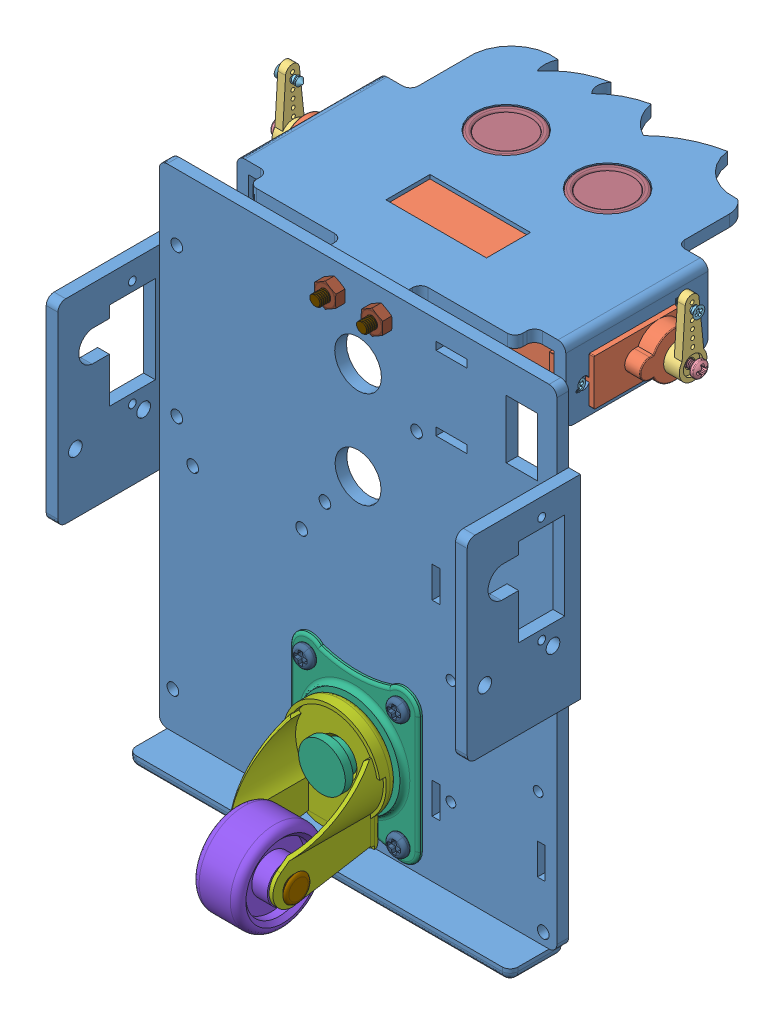
SolidWorks assembly DYOR_3D_OL_AR, configuration Predeterminado. Lengths in mm.
Overall size (109.66 136.43 112.93).
67 component instances, 23 part files, 18 mates.
Components (placement in the parent):
- Base-1: Base [Predeterminado] at (60.418 -80.9125 12.5389) size (108 128.45 29)
- AR1-1: AR1 [Predeterminado] at (-138.059 230.6023 -125.9386) size (34.06 21.84 31.9)
  - sg90-2: sg90 [Default] at (126.818 -193.0635 98.9775) x (0 0 1) z (0 -1 0) size (31.9 29.9 11.8)
  - SG90 plastic Horn-2: SG90 plastic Horn [Default] at (97.368 -198.9635 104.8775) x (0 0.999767 0.021606) z (0 -0.021606 0.999767) size (19.4 4 7.07)
  - (M2_3_mm)_90116A007_METRIC 316 SS PAN HEAD PHILLIPS MACHINE SCREW-2: (M2_3_mm)_90116A007_METRIC 316 SS PAN HEAD PHILLIPS MACHINE SCREW [90116A007] at (97.368 -198.9635 104.8775) x (0 0 1) z (-1 0 0) size (4 4 4.68)
  - M2x6 SelfTap Screw-1: M2x6 SelfTap Screw [Predeterminado] at (93.868 -186.4635 104.8775) x (0 0.924225 0.381849) z (-1 0 0) size (3.4 3.28 6)
  - M2x6 SelfTap Screw-3: M2x6 SelfTap Screw [Predeterminado] at (105.418 -198.9635 123.8775) x (0 0.924225 0.381849) z (-1 0 0) size (3.4 3.28 6)
  - M2x6 SelfTap Screw-5: M2x6 SelfTap Screw [Predeterminado] at (105.418 -198.9635 96.5775) x (0 0.924225 0.381849) z (-1 0 0) size (3.4 3.28 6)
- AR2-1: AR2 [Predeterminado] at (-145.0774 230.6023 -125.9386) size (34.06 21.82 31.9)
  - sg90-1: sg90 [Default] at (175.3764 -204.8635 98.9775) x (0 0 1) z (0 1 0) size (31.9 29.9 11.8)
  - SG90 plastic Horn-1: SG90 plastic Horn [Default] at (204.8264 -198.9635 104.8775) x (0 0.999858 0.016879) z (0 0.016879 -0.999858) size (19.4 4 7.07)
  - (M2_3_mm)_90116A007_METRIC 316 SS PAN HEAD PHILLIPS MACHINE SCREW-1: (M2_3_mm)_90116A007_METRIC 316 SS PAN HEAD PHILLIPS MACHINE SCREW [90116A007] at (204.8264 -198.9635 104.8775) x (0 0 -1) z (1 0 0) size (4 4 4.68)
  - M2x6 SelfTap Screw-2: M2x6 SelfTap Screw [Predeterminado] at (208.3264 -186.4635 104.8775) x (0 -0.924225 -0.381849) z (1 0 0) size (3.4 3.28 6)
  - M2x6 SelfTap Screw-4: M2x6 SelfTap Screw [Predeterminado] at (196.7764 -198.9635 123.8775) x (0 -0.924225 -0.381849) z (1 0 0) size (3.4 3.28 6)
  - M2x6 SelfTap Screw-6: M2x6 SelfTap Screw [Predeterminado] at (196.7764 -198.9635 96.5775) x (0 -0.924225 -0.381849) z (1 0 0) size (3.4 3.28 6)
- CA-1: CA [Predeterminado] at (-2.207 18.0036 0) size (33 45.94 43.2)
  - Caster Wheel-1: Caster Wheel [Default] at (57.6387 -78.841 57.7572) x (0 1 0) z (-1 0 0) size (45.94 37.59 33)
    - caster holder-1: caster holder [Default] at (-24.0751 44.7184 29.5137) x (1 0 0) z (0 0 -1) size (39 9.27 33)
    - holder-1: holder [Default] at (-1.5751 42.9484 46.0137) x (0 0 1) z (1 0 0) size (25 28.07 31.31)
    - caster wheel-1: caster wheel [Default] at (-15.6961 19.9484 46.0137) x (0.997275 0.073773 0) z (0 0 1) size (23 23 14)
    - Part4-1: Part4 [Default] at (-15.6961 19.9484 55.0137) x (-0.978448 0.206495 0) z (0 0 -1) size (7 7 20)
  - M3x6 Philips Screw-1: M3x6 Philips Screw [Predeterminado] at (23.625 -65.4161 13.5389) size (5.3 5.3 7.81)
  - M3x6 Philips Screw-2: M3x6 Philips Screw [Predeterminado] at (-0.375 -65.4161 13.5389) size (5.3 5.3 7.81)
  - M3x6 Philips Screw-3: M3x6 Philips Screw [Predeterminado] at (-0.375 -95.4161 13.5389) size (5.3 5.3 7.81)
  - M3x6 Philips Screw-4: M3x6 Philips Screw [Predeterminado] at (23.625 -95.4161 13.5389) size (5.3 5.3 7.81)
  - M3 Nut-1: M3 Nut [Predeterminado] at (23.625 -65.4161 11.0389) size (6.27 6.27 2.71)
  - M3 Nut-2: M3 Nut [Predeterminado] at (-0.375 -65.4161 11.0389) size (6.27 6.27 2.71)
  - M3 Nut-3: M3 Nut [Predeterminado] at (-0.375 -95.4161 11.0389) size (6.27 6.27 2.71)
  - M3 Nut-4: M3 Nut [Predeterminado] at (23.625 -95.4161 11.0389) size (6.27 6.27 2.71)
- HC-SR04 Ping Sensor-1: HC-SR04 Ping Sensor [Default] at (9.418 28.7888 -38.4617) x (0 0 -1) z (0 1 0) size (25.18 45 18.07)
  - PCB-1: PCB [Default] at origin size (20.5 45 1.75)
  - Transducer-1: Transducer [Default] at (0 -13 13.25) x (1 0 0) z (0 -1 0) size (15.88 12 15.88)
  - Transducer-2: Transducer [Default] at (0 13 13.25) x (1 0 0) z (0 -1 0) size (15.88 12 15.88)
  - 3 Pin Header 90 Degree-1: 3 Pin Header 90 Degree [Default] at (8.4275 0 -1.25) x (-1 0 0) z (0 -1 0) size (8 7.82 10)
  - 14 Pin SMT-1: 14 Pin SMT [Default] at (-0.35 -18.5 -0.85) x (0 -1 0) z (1 0 0) size (6 1.6 8.8)
  - 14 Pin SMT-2: 14 Pin SMT [Default] at (0 -0.3826 -0.85) x (1 0 0) z (0 1 0) size (6 1.6 8.8)
  - 14 Pin SMT-3: 14 Pin SMT [Default] at (0 17.5274 -0.85) x (1 0 0) z (0 1 0) size (6 1.6 8.8)
  - Cap1 SMT-1: Cap1 SMT [Default] at (-1.755 7.4774 -0.9689) x (0 1 0) z (-1 0 0) size (4.5 1.84 1.75)
  - Cap1 SMT-2: Cap1 SMT [Default] at (6.835 7.4774 -0.9689) x (0 1 0) z (-1 0 0) size (4.5 1.84 1.75)
  - Cap1 SMT-3: Cap1 SMT [Default] at (-6.835 7.4774 -0.9689) x (0 1 0) z (-1 0 0) size (4.5 1.84 1.75)
  - Cap1 SMT-4: Cap1 SMT [Default] at (4.295 7.4774 -0.9689) x (0 1 0) z (-1 0 0) size (4.5 1.84 1.75)
  - Cap1 SMT-5: Cap1 SMT [Default] at (1.755 7.4774 -0.9689) x (0 1 0) z (-1 0 0) size (4.5 1.84 1.75)
  - Cap1 SMT-6: Cap1 SMT [Default] at (-4.295 7.4774 -0.9689) x (0 1 0) z (-1 0 0) size (4.5 1.84 1.75)
  - HC-SR04 Crystal-1: HC-SR04 Crystal [Default] at (-8.3 0 1.75) x (0 -1 0) z (0 0 1) size (10 3.5 2.7)
- M3x10 Philips Screw-1: M3x10 Philips Screw [Predeterminado] at (3.418 36.0388 7.5389) x (-0.459458 -0.8882 0) z (0 0 -1) size (5.3 5.3 11.8)
- M3x10 Philips Screw-2: M3x10 Philips Screw [Predeterminado] at (15.418 36.0388 7.5389) x (-0.386504 -0.922288 0) z (0 0 -1) size (5.3 5.3 11.8)
- M3 Nut-1: M3 Nut [Predeterminado] at (15.418 36.0388 16.5389) size (6.27 6.27 2.71)
- M3 Nut-2: M3 Nut [Predeterminado] at (3.418 36.0388 16.5389) size (6.27 6.27 2.71)
- Front_OL_AR-1: Front_OL_AR [Predeterminado] at (-51.1718 39.5388 -46.4824) x (1 0 0) z (0 1 0) size (84.34 72.35 18.8)
- OLED_0.91_128x32-1: OLED_0.91_128x32 [Predeterminado] at (10.618 39.0288 -13.1554) x (1 0 0) z (0 1 0) size (38.3 12.1 11.46)
  - OLED_0.91_128x32.stp-1: OLED_0.91_128x32.stp [Predeterminado] at origin size (38.3 12.1 11.46)
    - OLED_0.91_128x32.stp-1: OLED_0.91_128x32.stp [Predeterminado] at origin size (38.3 12.1 2.57)
    - Pin Header 4 x 1 TH 2.54mm Pitch.stp-1: Pin Header 4 x 1 TH 2.54mm Pitch.stp [Predeterminado] at (-17.55 -3.81 -2.6) size (2.54 10.16 11.43)
    - RESC-0603.stp-1: RESC-0603.stp [Predeterminado] at (4.3 -5.3 0) x (1 0 0) z (0 0 -1) size (1.7 0.9 0.55)
    - RESC-0603.stp-2: RESC-0603.stp [Predeterminado] at (4.3 -3.8 0) x (1 0 0) z (0 0 -1) size (1.7 0.9 0.55)
    - RESC-0603.stp-3: RESC-0603.stp [Predeterminado] at (4.3 -2.3 0) x (1 0 0) z (0 0 -1) size (1.7 0.9 0.55)
    - RESC-0603.stp-4: RESC-0603.stp [Predeterminado] at (4.3 -0.8 0) x (1 0 0) z (0 0 -1) size (1.7 0.9 0.55)
    - RESC-0603.stp-5: RESC-0603.stp [Predeterminado] at (4.3 0.7 0) x (1 0 0) z (0 0 -1) size (1.7 0.9 0.55)
    - RESC-0603.stp-6: RESC-0603.stp [Predeterminado] at (4.3 2.2 0) x (1 0 0) z (0 0 -1) size (1.7 0.9 0.55)
    - RESC-0603.stp-7: RESC-0603.stp [Predeterminado] at (4.3 3.7 0) x (1 0 0) z (0 0 -1) size (1.7 0.9 0.55)
    - RESC-0603.stp-8: RESC-0603.stp [Predeterminado] at (4.3 5.2 0) x (1 0 0) z (0 0 -1) size (1.7 0.9 0.55)
    - RESC-0603.stp-9: RESC-0603.stp [Predeterminado] at (-1.4 -3.06 0) x (1 0 0) z (0 0 -1) size (1.7 0.9 0.55)
    - RESC-0603.stp-10: RESC-0603.stp [Predeterminado] at (-1.4 -1.56 0) x (1 0 0) z (0 0 -1) size (1.7 0.9 0.55)
    - RESC-0603.stp-11: RESC-0603.stp [Predeterminado] at (-1.4 -0.06 0) x (1 0 0) z (0 0 -1) size (1.7 0.9 0.55)
    - RESC-0603.stp-12: RESC-0603.stp [Predeterminado] at (-1.4 1.44 0) x (1 0 0) z (0 0 -1) size (1.7 0.9 0.55)
    - RESC-0603.stp-13: RESC-0603.stp [Predeterminado] at (-1.4 2.94 0) x (1 0 0) z (0 0 -1) size (1.7 0.9 0.55)
    - 2SD0601A.stp-1: 2SD0601A.stp [Predeterminado] at (-9.8 -1.3 -0.08) x (1 0 0) z (0 1 0) size (2.76 1.18 2.9)
Mates (geometry in assembly coordinates):
- Coincidente23: coincident: plane of Base-1 through (-39.582 40.5388 12.5389) normal (0 0 1); plane of CA-1/Caster Wheel-1/caster holder-1 through (9.418 -17.6143 12.5389) normal (0 0 -1)
- Concéntrica1: concentric: circle of Base-1; circle of CA-1/Caster Wheel-1/caster holder-1
- Concéntrica2: concentric: circle of Base-1; circle of CA-1/Caster Wheel-1/caster holder-1
- Coincidente30: coincident: plane of Base-1 through (-39.582 40.5388 12.5389) normal (0 0 1); plane of M3 Nut-1 through (15.418 36.0388 12.5389) normal (0 0 -1)
- Coincidente31: coincident: plane of Base-1 through (-39.582 40.5388 12.5389) normal (0 0 1); plane of M3 Nut-2 through (3.418 36.0388 12.5389) normal (0 0 -1)
- Concéntrica7: concentric: circle of Base-1; circle of M3 Nut-1
- Concéntrica8: concentric: circle of Base-1; circle of M3 Nut-2
- Coincidente32: coincident: plane of Base-1 through (-39.582 40.5388 9.5389) normal (0 0 -1); plane of Front_OL_AR-1 through (-0.582 42.5388 9.5389) normal (0 0 1)
- Concéntrica9: concentric: circle of Base-1; circle of Front_OL_AR-1
- Paralelo1: parallel: plane of Base-1 through (-39.582 42.5388 9.5389) normal (0 1 0); plane of Front_OL_AR-1 through (45.699 42.5388 -36.9614) normal (0 1 0)
- Concéntrica10: concentric: circle of HC-SR04 Ping Sensor-1/Transducer-1; circle of Front_OL_AR-1
- Concéntrica11: concentric: circle of HC-SR04 Ping Sensor-1/Transducer-2; circle of Front_OL_AR-1
- Coincidente34: coincident: plane of HC-SR04 Ping Sensor-1/Transducer-2 through (-3.582 42.5388 -46.4017) normal (0 1 0); plane of Front_OL_AR-1 through (45.699 42.5388 -36.9614) normal (0 1 0)
- Coincidente35: coincident: plane of AR2-1/sg90-1 through (48.699 25.7388 -31.6611) normal (1 0 0); plane of Front_OL_AR-1 through (48.699 23.7388 -34.9614) normal (-1 0 0)
- Coincidente36: coincident: plane of AR1-1/sg90-2 through (-29.641 37.5388 -31.6611) normal (-1 0 0); plane of Front_OL_AR-1 through (-29.641 23.7388 -34.9614) normal (1 0 0)
- Coincidente37: coincident: plane of Front_OL_AR-1 through (-8.532 40.5388 -7.1054) normal (1 0 0); plane of OLED_0.91_128x32-1/OLED_0.91_128x32.stp-1/OLED_0.91_128x32.stp-1 through (-8.532 39.0288 -19.2054) normal (-1 0 0)
- Coincidente38: coincident: plane of Front_OL_AR-1 through (29.768 40.5388 -7.1054) normal (0 0 -1); plane of OLED_0.91_128x32-1/OLED_0.91_128x32.stp-1/OLED_0.91_128x32.stp-1 through (-8.532 39.0288 -7.1054) normal (0 0 1)
- Distancia1: distance = 1 mm: plane of OLED_0.91_128x32-1/OLED_0.91_128x32.stp-1/OLED_0.91_128x32.stp-1 through (9.418 41.5388 -13.1554) normal (0 1 0); plane of Front_OL_AR-1 through (45.699 42.5388 -36.9614) normal (0 1 0)
